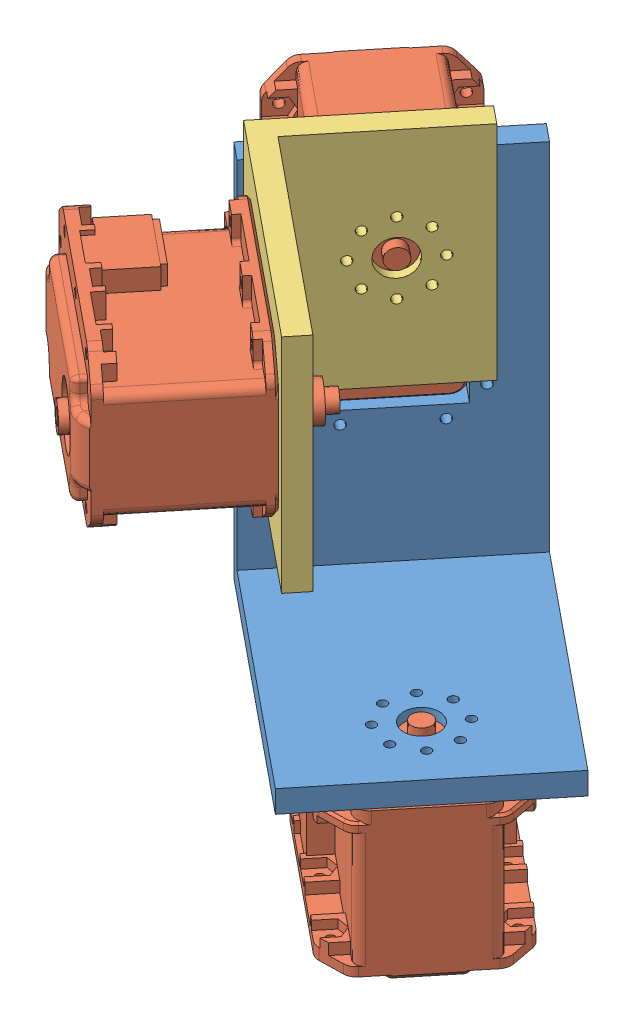
SolidWorks assembly ball_joint, configuration Default. Lengths in mm.
Overall size (104.35 132.75 118.89).
5 component instances, 3 part files, 13 mates.
Components (placement in the parent):
- connector_1-1: connector_1 [Default] at (-8.086 54.3394 121.3064) x (0.774879 0 0.632109) z (-0.632109 0 0.774879) size (65.5 85 50)
- MX-28AR-1: MX-28AR [默认] at (-3.9064 122.3394 92.4528) x (0.632109 0 -0.774879) z (0.774879 0 0.632109) size (35.6 50.71 45.1)
- MX-28AR-2: MX-28AR [默认] at (46.0733 33.8394 133.2238) x (-0.632109 0 0.774879) z (0 1 0) size (35.6 50.71 45.1)
- connector_2-1: connector_2 [Default] at (-3.192 97.3394 124.0081) x (0.632109 0 -0.774879) z (0 -1 0) size (40 60 50)
- MX-28AR-3: MX-28AR [默认] at (20.6461 122.3394 162.812) x (0 1 0) z (0.632109 0 -0.774879) size (35.6 50.71 45.1)
Mates (geometry in assembly coordinates):
- Coincident1: coincident anti-aligned: plane of MX-28AR-1 through (7.7167 122.3394 101.9344) normal (0.774879 0 0.632109); plane of connector_1-1 through (-8.086 59.3394 121.3064) normal (-0.774879 0 -0.632109)
- Concentric1: concentric aligned: circle of connector_1-1; circle of MX-28AR-1
- Coincident3: coincident anti-aligned: plane of connector_1-1 through (-8.086 54.3394 121.3064) normal (0 -1 0); plane of MX-28AR-2 through (46.0733 54.3394 133.2238) normal (0 1 0)
- Concentric4: concentric aligned: cylinder of connector_1-1 through (46.0733 59.3394 133.2238) axis (0 -1 0) radius 4; cylinder of MX-28AR-2 through (46.0733 60.0944 133.2238) axis (0 -1 0) radius 4
- Coincident5: coincident anti-aligned: plane of MX-28AR-1 through (11.9786 122.3394 105.411) normal (0.774879 0 0.632109); plane of connector_2-1 through (-3.192 97.3394 124.0081) normal (-0.774879 0 -0.632109)
- Concentric5: concentric aligned: cylinder of MX-28AR-1 through (16.438 122.3394 109.0488) axis (-0.774879 0 -0.632109) radius 4; cylinder of connector_2-1 through (15.853 122.3394 108.5716) axis (-0.774879 0 -0.632109) radius 4
- Coincident6: coincident anti-aligned: plane of MX-28AR-3 through (30.1278 122.3394 151.1888) normal (0.632109 0 -0.774879); plane of connector_2-1 through (0.6823 97.3394 127.1687) normal (-0.632109 0 0.774879)
- Concentric8: concentric aligned: cylinder of connector_2-1 through (58.8991 107.3394 123.0381) axis (-0.632109 0 0.774879) radius 1.025; cylinder of MX-28AR-3 through (24.1331 107.3394 165.6565) axis (-0.632109 0 0.774879) radius 1.025
- Concentric9: concentric aligned: cylinder of connector_2-1 through (32.5532 137.3394 101.5464) axis (-0.632109 0 0.774879) radius 1.025; cylinder of MX-28AR-3 through (-2.2128 137.3394 144.1648) axis (-0.632109 0 0.774879) radius 1.025
- Concentric10: concentric aligned: cylinder of connector_1-1 through (48.9897 92.8394 154.9608) axis (-0.774879 0 -0.632109) radius 1.025; cylinder of MX-28AR-1 through (-13.3881 92.8394 104.076) axis (-0.774879 0 -0.632109) radius 1.025
- Parallel1: parallel aligned: plane of connector_1-1 through (23.5195 59.3394 82.5624) normal (0.632109 0 -0.774879); plane of MX-28AR-2 through (61.9741 46.8394 123.2236) normal (0.632109 0 -0.774879)
- Parallel2: parallel aligned: plane of connector_1-1 through (-8.086 139.3394 121.3064) normal (0 1 0); plane of connector_2-1 through (0.6823 147.3394 127.1687) normal (0 1 0)
- Parallel3: parallel aligned: plane of connector_2-1 through (0.6823 147.3394 127.1687) normal (0 1 0); plane of MX-28AR-3 through (-12.8324 140.1394 152.2787) normal (0 1 0)
